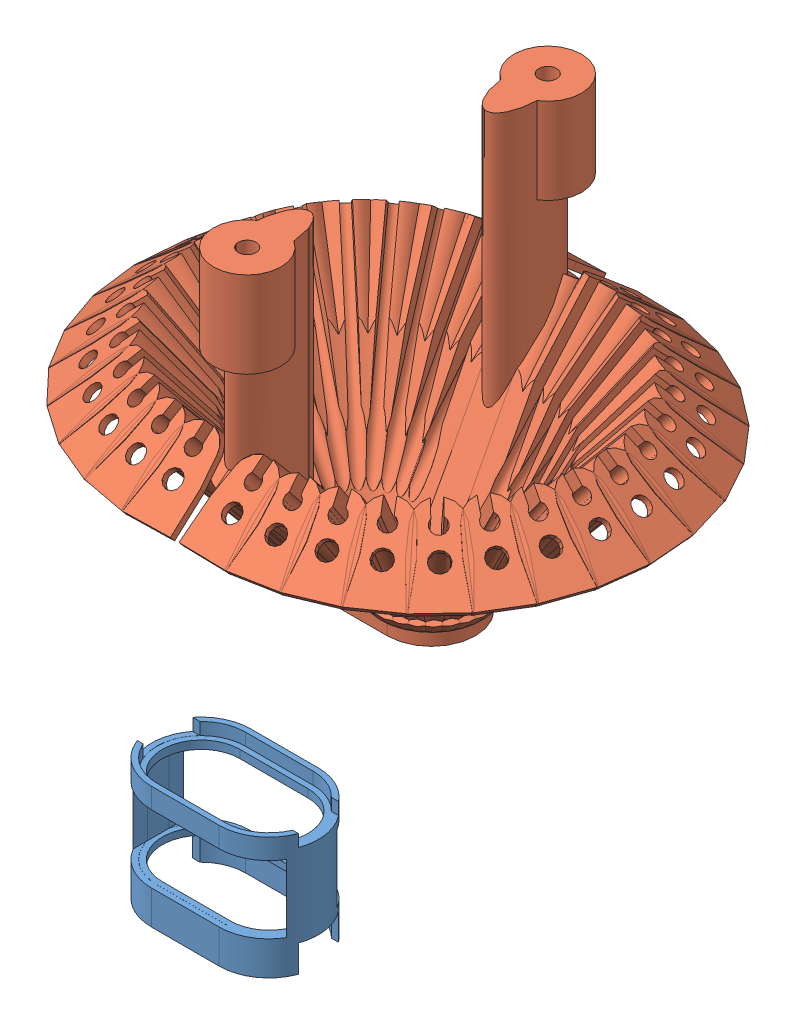
SolidWorks assembly Assem4, configuration Default. Lengths in mm.
Overall size (78.2 60.93 72.57).
2 component instances, 2 part files, 0 mates.
Components (placement in the parent):
- AlingmentJigBase-1: AlingmentJigBase [Default] at (3.5332 -1.1572 10.8137) size (12.33 9 7.33)
- bilat-ca1-30tt-drive-cone-caphpjig-1: bilat-ca1-30tt-drive-cone-caphpjig [Default] at (-5.5536 0.4721 -12.173) size (78.2 53.6 72.57)
